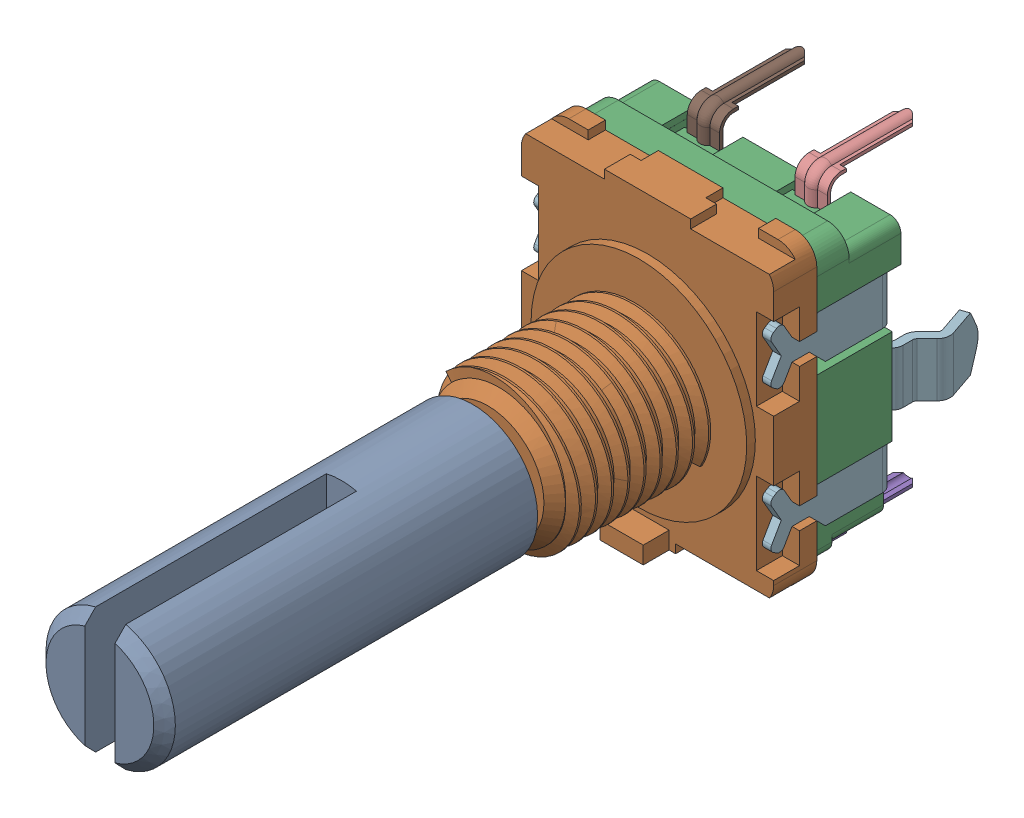
SolidWorks assembly Open CASCADE STEP translator 6.8 1.7.1, configuration Défaut. Lengths in mm.
Overall size (13.1 15.13 35.07).
17 component instances, 7 part files, 0 mates.
Components (placement in the parent):
- Body_1-1: Body_1 [Défaut] at (2.5 -6.5 0) x (-1 0 0) z (0 0 1) size (13.1 15.13 35.07)
  - Imported-1: Imported [Défaut] at (0 0 13.6) size (6 6 18)
  - Imported_2-1: Imported_2 [Défaut] at (0 0 3.443) size (11.7 13.8 9.4)
  - Imported_3-1: Imported_3 [Défaut] at (-0.85 -0.6436 6.5892) size (11.7 13.3 3.9)
  - Imported-2: Imported [Défaut] at (0 0 6.6326) size (13.1 14.95 9.45)
    - Imported_2-1: Imported_2 [Défaut] at (-2.5 7.575 -10.2243) x (0 -1 0) z (0 0 1) size (2.34 1.5 6.65)
      - SOLID-1: SOLID [Défaut] at origin size (0.6 1.5 0.15)
      - SOLID_2-1: SOLID_2 [Défaut] at origin size (2.15 1.5 6.65)
    - Imported_2-2: Imported_2 [Défaut] at (0 7.575 -10.2243) x (0 -1 0) z (0 0 1) size (2.34 1.5 6.65)
      - SOLID-1: SOLID [Défaut] at origin size (0.6 1.5 0.15)
      - SOLID_2-1: SOLID_2 [Défaut] at origin size (2.15 1.5 6.65)
    - Imported_2-3: Imported_2 [Défaut] at (2.5 7.575 -10.2243) x (0 -1 0) z (0 0 1) size (2.34 1.5 6.65)
      - SOLID-1: SOLID [Défaut] at origin size (0.6 1.5 0.15)
      - SOLID_2-1: SOLID_2 [Défaut] at origin size (2.15 1.5 6.65)
    - Imported_4-1: Imported_4 [Défaut] at (-2.5 -7.075 -10.2243) x (0 1 0) z (0 0 1) size (2.15 1.5 4.73)
    - Imported_4-2: Imported_4 [Défaut] at (2.5 -7.075 -10.2243) x (0 1 0) z (0 0 1) size (2.15 1.5 4.73)
    - Imported_5-1: Imported_5 [Défaut] at (-24.7094 3.8245 8.4125) size (13.1 9.9 9.18)
